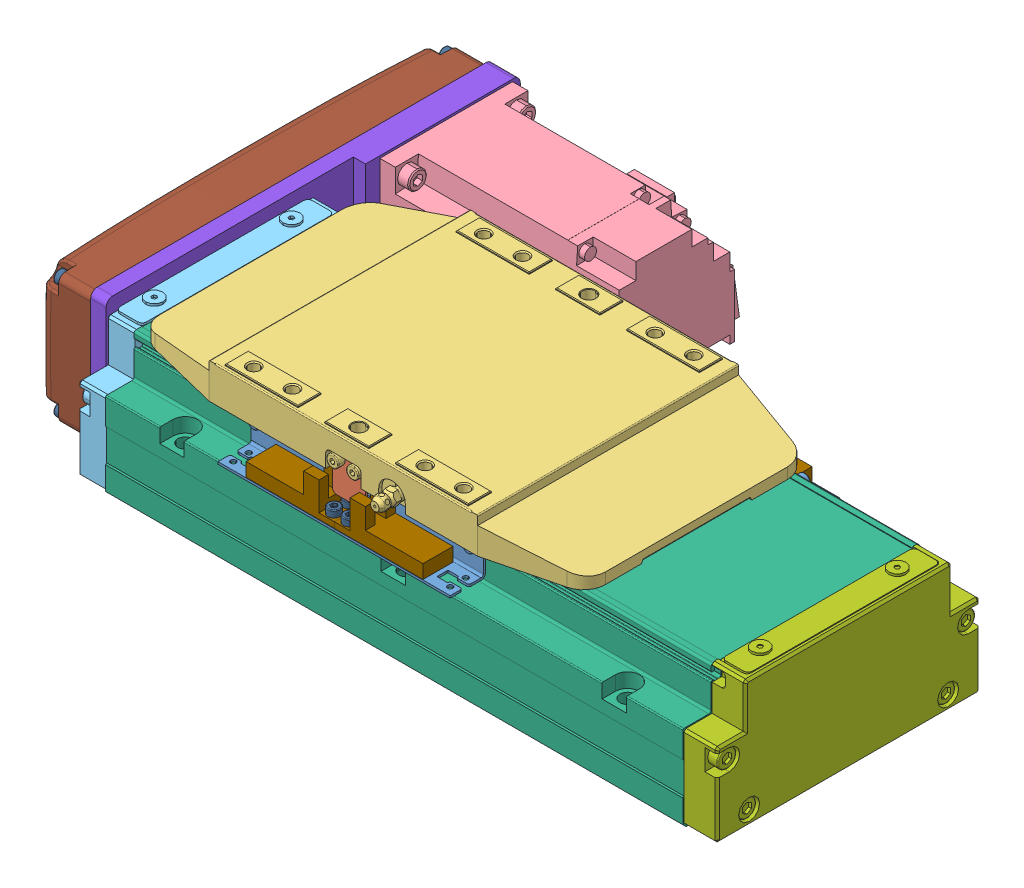
SolidWorks assembly G12-BR-400W, configuration Default. Lengths in mm.
Overall size (320.5 76 207.1).
25 component instances, 11 part files, 62 mates.
Components (placement in the parent):
- 304开关座片G5-12^G12-BR-400W-1: 304开关座片G5-12^G12-BR-400W [Default] at (209 38.5 -47.2) x (-1 0 0) z (0 0 -1) size (52.5 15.7 21) (virtual)
- 304开关座片G5-12^G12-BR-400W-2: 304开关座片G5-12^G12-BR-400W [Default] at (54 38.5 47.2) size (52.5 15.7 21) (virtual)
- 304开关座片G5-12^G12-BR-400W-3: 304开关座片G5-12^G12-BR-400W [Default] at (106.5 38.5 47.2) size (52.5 15.7 21) (virtual)
- 304感应片G8-12^G12-BR-400W-1: 304感应片G8-12^G12-BR-400W [Default] at (106.5 56.7 0) x (1 0 0) z (0 0 -1) size (15 17 1) (virtual)
- 304感应片G8-12^G12-BR-400W-2: 304感应片G8-12^G12-BR-400W [Default] at (106.5 56.7 0) x (-1 0 0) z (0 0 1) size (15 17 1) (virtual)
- 滑台G12^G12-BR-400W-1: 滑台G12^G12-BR-400W [Default] at (106.5 59.3 0) size (201.5 16.7 133.6) (virtual)
- 三菱400w^G12-BR-400W-1: 三菱400w^G12-BR-400W [Default] at (-7.5 32.5 -101.5) x (0 0 -1) z (0 -1 0) size (68.8 128.3 60) (virtual)
- 丝杆座板G12^G12-BR-400W-1: 丝杆座板G12^G12-BR-400W [Default] at origin size (20.5 58.7 119) (virtual)
- 复件 复件 底座GY12+211^G12-BR-400W-1: 复件 复件 底座GY12+211^G12-BR-400W [默认] x (0 0 -1) z (1 0 0) size (120 58 261) (virtual)
- 塑胶轴承座G12^G12-BR-400W-2: 塑胶轴承座G12^G12-BR-400W [Default] at (261 0 0) size (15 58.9 119) (virtual)
- 电机板G12-BLR-P60^G12-BR-400W-1: 电机板G12-BLR-P60^G12-BR-400W [Default] at (0 65 0) x (1 0 0) z (0 0 -1) size (12.5 62 181.75) (virtual)
- 复件 复件 光电开关EE-SX674^G12-BR-400W-1: 复件 复件 光电开关EE-SX674^G12-BR-400W [默认] at (66.5 41.8 49.4) size (40 15.5 13.6) (virtual)
- 复件 复件 光电开关EE-SX674^G12-BR-400W-2: 复件 复件 光电开关EE-SX674^G12-BR-400W [默认] at (146.5 41.8 63) x (-1 0 0) z (0 0 -1) size (40 15.5 13.6) (virtual)
- 复件 复件 光电开关EE-SX674^G12-BR-400W-3: 复件 复件 光电开关EE-SX674^G12-BR-400W [默认] at (196.5 41.8 -49.4) x (-1 0 0) z (0 0 -1) size (40 15.5 13.6) (virtual)
- hexagon socket head cap screws gb-5: hexagon socket head cap screws gb [GB_FASTENER_SCREWS_HSHCS M3X5-N] at (160 47.4 -52.7) x (0 -1 0) z (0 0 1) size (8 5.5 5.5)
- hexagon socket head cap screws gb-6: hexagon socket head cap screws gb [GB_FASTENER_SCREWS_HSHCS M3X5-N] at (160 47.4 -59.7) x (0 -1 0) z (0 0 1) size (8 5.5 5.5)
- hexagon socket head cap screws gb-7: hexagon socket head cap screws gb [GB_FASTENER_SCREWS_HSHCS M3X5-N] at (103 47.4 59.7) x (0 -1 0) z (0 0 1) size (8 5.5 5.5)
- hexagon socket head cap screws gb-8: hexagon socket head cap screws gb [GB_FASTENER_SCREWS_HSHCS M3X5-N] at (103 47.4 52.7) x (0 -1 0) z (0 0 1) size (8 5.5 5.5)
- hexagon socket head cap screws gb-9: hexagon socket head cap screws gb [GB_FASTENER_SCREWS_HSHCS M3X5-N] at (110 47.4 59.7) x (0 -1 0) z (0 0 1) size (8 5.5 5.5)
- hexagon socket head cap screws gb-10: hexagon socket head cap screws gb [GB_FASTENER_SCREWS_HSHCS M3X5-N] at (110 47.4 52.7) x (0 -1 0) z (0 0 1) size (8 5.5 5.5)
- hexagon socket head cap screws gb-11: hexagon socket head cap screws gb [GB_FASTENER_SCREWS_HSHCS M3X20-N] at (-38 58.5 -131.125) size (23 5.5 5.5)
- hexagon socket head cap screws gb-12: hexagon socket head cap screws gb [GB_FASTENER_SCREWS_HSHCS M3X20-N] at (-38 6.5 -131.125) size (23 5.5 5.5)
- hexagon socket head cap screws gb-13: hexagon socket head cap screws gb [GB_FASTENER_SCREWS_HSHCS M3X20-N] at (-38 6.5 42.875) size (23 5.5 5.5)
- hexagon socket head cap screws gb-14: hexagon socket head cap screws gb [GB_FASTENER_SCREWS_HSHCS M3X20-N] at (-38 58.5 42.875) size (23 5.5 5.5)
- 复件 同步轮罩壳G12^G12-BR-400W-2: 复件 同步轮罩壳G12^G12-BR-400W [默认] at (-43.3 32.5 -44.125) x (0 0 1) z (0 1 0) size (180.75 24.5 61.51) (virtual)
Mates (geometry in assembly coordinates):
- 宽度3: width: plane of 丝杆座板G12^G12-BR-400W-1 through (-13 37.5 59.5) normal (0 0 1); plane of 丝杆座板G12^G12-BR-400W-1 through (-13 2 -59.5) normal (0 0 -1); plane of 复件 复件 底座GY12+211^G12-BR-400W-1 through (261 12.5 -59.5) normal (0 0 -1); plane of 复件 复件 底座GY12+211^G12-BR-400W-1 through (261 26.5 59.5) normal (0 0 1)
- 距离2: distance = 1 mm: plane of 复件 复件 底座GY12+211^G12-BR-400W-1 through (261 0 58.5) normal (0 -1 0); plane of 丝杆座板G12^G12-BR-400W-1 through (-13 1 58.5) normal (0 -1 0)
- 重合11: coincident: plane of 丝杆座板G12^G12-BR-400W-1 through (0 0 0) normal (1 0 0); plane of 复件 复件 底座GY12+211^G12-BR-400W-1 through (0 57 46.2) normal (-1 0 0)
- 宽度8: width: plane of 滑台G12^G12-BR-400W-1 through (45.75 76 59) normal (0 0 1); plane of 滑台G12^G12-BR-400W-1 through (167.25 76 -59) normal (0 0 -1); plane of 复件 复件 底座GY12+211^G12-BR-400W-1 through (261 12.5 -59.5) normal (0 0 -1); plane of 复件 复件 底座GY12+211^G12-BR-400W-1 through (261 26.5 59.5) normal (0 0 1)
- 距离5: distance = 76 mm: plane of 滑台G12^G12-BR-400W-1 through (15.75 76 -41.214) normal (0 1 0); plane of 复件 复件 底座GY12+211^G12-BR-400W-1 through (261 0 58.5) normal (0 -1 0)
- 宽度9: width: plane of 304感应片G8-12^G12-BR-400W-2 through (99 64 56.5) normal (-1 0 0); plane of 304感应片G8-12^G12-BR-400W-2 through (114 51 56.5) normal (1 0 0); plane of 滑台G12^G12-BR-400W-1 through (98.5 65 55.5) normal (1 0 0); plane of 滑台G12^G12-BR-400W-1 through (114.5 59.3 55.5) normal (-1 0 0)
- 距离6: distance = 10.3 mm: plane of 304感应片G8-12^G12-BR-400W-2 through (101 49 56.5) normal (0 -1 0); plane of 滑台G12^G12-BR-400W-1 through (15.75 59.3 -41.214) normal (0 -1 0)
- 距离7: distance = 2.5 mm: plane of 304感应片G8-12^G12-BR-400W-2 through (112 51 56.5) normal (0 0 1); plane of 滑台G12^G12-BR-400W-1 through (45.75 76 59) normal (0 0 1)
- 宽度10: width: plane of 304感应片G8-12^G12-BR-400W-1 through (99 51 -56.5) normal (-1 0 0); plane of 304感应片G8-12^G12-BR-400W-1 through (114 64 -56.5) normal (1 0 0); plane of 滑台G12^G12-BR-400W-1 through (98.5 65 -55.5) normal (1 0 0); plane of 滑台G12^G12-BR-400W-1 through (114.5 59.3 -55.5) normal (-1 0 0)
- 距离8: distance = 2.5 mm: plane of 304感应片G8-12^G12-BR-400W-1 through (101 51 -56.5) normal (0 0 -1); plane of 滑台G12^G12-BR-400W-1 through (167.25 76 -59) normal (0 0 -1)
- 距离9: distance = 10.3 mm: plane of 304感应片G8-12^G12-BR-400W-1 through (112 49 -56.5) normal (0 -1 0); plane of 滑台G12^G12-BR-400W-1 through (15.75 59.3 -41.214) normal (0 -1 0)
- 宽度14: width: plane of 塑胶轴承座G12^G12-BR-400W-2 through (276 37.5 59.5) normal (0 0 1); plane of 塑胶轴承座G12^G12-BR-400W-2 through (276 2 -59.5) normal (0 0 -1); plane of 复件 复件 底座GY12+211^G12-BR-400W-1 through (261 12.5 -59.5) normal (0 0 -1); plane of 复件 复件 底座GY12+211^G12-BR-400W-1 through (261 26.5 59.5) normal (0 0 1)
- 重合23: coincident: plane of 复件 复件 底座GY12+211^G12-BR-400W-1 through (261 57 46.2) normal (1 0 0); plane of 塑胶轴承座G12^G12-BR-400W-2 through (261 0 0) normal (-1 0 0)
- 距离10: distance = 1 mm: plane of 塑胶轴承座G12^G12-BR-400W-2 through (276 1 58.5) normal (0 -1 0); plane of 复件 复件 底座GY12+211^G12-BR-400W-1 through (261 0 58.5) normal (0 -1 0)
- 距离11: distance = 67 mm: plane of 304开关座片G5-12^G12-BR-400W-2 through (54 42.8 49.2) normal (-1 0 0); plane of 丝杆座板G12^G12-BR-400W-1 through (-13 0 0) normal (-1 0 0)
- 距离12: distance = 105 mm: plane of 304开关座片G5-12^G12-BR-400W-3 through (159 42.8 49.2) normal (1 0 0); plane of 304开关座片G5-12^G12-BR-400W-2 through (54 42.8 49.2) normal (-1 0 0)
- 宽度15: width: plane of 复件 复件 底座GY12+211^G12-BR-400W-1 through (261 51.25 46.2) normal (0 1 0); plane of 复件 复件 底座GY12+211^G12-BR-400W-1 through (261 54.75 46.7) normal (0 -1 0); cylinder of 304开关座片G5-12^G12-BR-400W-2 through (58 53 42.2) axis (0 0 -1) radius 2.75
- 重合28: coincident: plane of 304开关座片G5-12^G12-BR-400W-2 through (106.5 40.8 63.2) normal (0 -1 0); plane of 304开关座片G5-12^G12-BR-400W-3 through (159 40.8 63.2) normal (0 -1 0)
- 重合29: coincident: plane of 304开关座片G5-12^G12-BR-400W-2 through (106.5 56.5 48.2) normal (0 0 1); plane of 304开关座片G5-12^G12-BR-400W-3 through (159 56.5 48.2) normal (0 0 1)
- 重合30: coincident: plane of 304开关座片G5-12^G12-BR-400W-2 through (106.5 42.8 47.2) normal (0 0 -1); plane of 复件 复件 底座GY12+211^G12-BR-400W-1 through (261 50.75 47.2) normal (0 0 1)
- 宽度16: width: plane of 复件 复件 底座GY12+211^G12-BR-400W-1 through (261 51.25 -46.7) normal (0 1 0); plane of 复件 复件 底座GY12+211^G12-BR-400W-1 through (261 54.75 -46.2) normal (0 -1 0); cylinder of 304开关座片G5-12^G12-BR-400W-1 through (205 53 -42.2) axis (0 0 1) radius 2.75
- 重合36: coincident: plane of 304开关座片G5-12^G12-BR-400W-1 through (156.5 42.8 -47.2) normal (0 0 1); plane of 复件 复件 底座GY12+211^G12-BR-400W-1 through (261 40 -47.2) normal (0 0 -1)
- 重合39: coincident: plane of 丝杆座板G12^G12-BR-400W-1 through (-13 0 0) normal (-1 0 0); plane of 电机板G12-BLR-P60^G12-BR-400W-1 through (-13 60.5 -132) normal (1 0 0)
- 重合43: coincident: plane of 三菱400w^G12-BR-400W-1 through (-7.5 32.5 -101.5) normal (-1 0 0); plane of 电机板G12-BLR-P60^G12-BR-400W-1 through (-7.5 60.5 -132) normal (1 0 0)
- 距离15: distance = 12.75 mm: plane of 复件 复件 底座GY12+211^G12-BR-400W-1 through (261 26.5 59.5) normal (0 0 1); plane of 电机板G12-BLR-P60^G12-BR-400W-1 through (-59.5 60.5 46.75) normal (0 0 1)
- 距离16: distance = 1.5 mm: plane of 电机板G12-BLR-P60^G12-BR-400W-1 through (-59.5 1.5 43.75) normal (0 -1 0); plane of 复件 复件 底座GY12+211^G12-BR-400W-1 through (261 0 58.5) normal (0 -1 0)
- 距离17: distance = 11.5 mm: plane of 复件 复件 底座GY12+211^G12-BR-400W-1 through (261 27 -60) normal (0 0 -1); plane of 三菱400w^G12-BR-400W-1 through (67 62.5 -71.5) normal (0 0 1)
- 宽度19: width: plane of 电机板G12-BLR-P60^G12-BR-400W-1 through (-59.5 1.5 43.75) normal (0 -1 0); plane of 电机板G12-BLR-P60^G12-BR-400W-1 through (-59.5 63.5 -132) normal (0 1 0); plane of 三菱400w^G12-BR-400W-1 through (67 62.5 -131.5) normal (0 1 0); plane of 三菱400w^G12-BR-400W-1 through (67 2.5 -71.5) normal (0 -1 0)
- 距离18: distance = 67 mm: plane of 304开关座片G5-12^G12-BR-400W-1 through (209 42.8 -49.2) normal (1 0 0); plane of 塑胶轴承座G12^G12-BR-400W-2 through (276 0 0) normal (1 0 0)
- 宽度20: width: plane of 304开关座片G5-12^G12-BR-400W-2 through (54 42.8 49.2) normal (-1 0 0); plane of 304开关座片G5-12^G12-BR-400W-3 through (159 42.8 49.2) normal (1 0 0); plane of 304感应片G8-12^G12-BR-400W-2 through (114 51 56.5) normal (1 0 0); plane of 304感应片G8-12^G12-BR-400W-2 through (99 64 56.5) normal (-1 0 0)
- 同心7: concentric: cylinder of 304开关座片G5-12^G12-BR-400W-2 through (103 43.5 59.7) axis (0 -1 0) radius 1.23; cylinder of 复件 复件 光电开关EE-SX674^G12-BR-400W-1 through (103 30.8 59.7) axis (0 1 0) radius 1.75
- 同心8: concentric: cylinder of 304开关座片G5-12^G12-BR-400W-2 through (103 43.5 52.7) axis (0 -1 0) radius 1.23; cylinder of 复件 复件 光电开关EE-SX674^G12-BR-400W-1 through (103 30.8 52.7) axis (0 1 0) radius 1.75
- 重合44: coincident: plane of 304开关座片G5-12^G12-BR-400W-2 through (106.5 41.8 49.2) normal (0 1 0); plane of 复件 复件 光电开关EE-SX674^G12-BR-400W-1 through (106.5 41.8 63) normal (0 -1 0)
- 重合45: coincident: plane of 304开关座片G5-12^G12-BR-400W-3 through (159 41.8 49.2) normal (0 1 0); plane of 复件 复件 光电开关EE-SX674^G12-BR-400W-2 through (106.5 41.8 49.4) normal (0 -1 0)
- 同心9: concentric: cylinder of 304开关座片G5-12^G12-BR-400W-3 through (110 43.5 59.7) axis (0 -1 0) radius 1.23; cylinder of 复件 复件 光电开关EE-SX674^G12-BR-400W-2 through (110 30.8 59.7) axis (0 1 0) radius 1.75
- 同心10: concentric: cylinder of 304开关座片G5-12^G12-BR-400W-3 through (110 43.5 52.7) axis (0 -1 0) radius 1.23; cylinder of 复件 复件 光电开关EE-SX674^G12-BR-400W-2 through (110 30.8 52.7) axis (0 1 0) radius 1.75
- 重合46: coincident: plane of 304开关座片G5-12^G12-BR-400W-1 through (156.5 41.8 -49.2) normal (0 1 0); plane of 复件 复件 光电开关EE-SX674^G12-BR-400W-3 through (156.5 41.8 -63) normal (0 -1 0)
- 同心11: concentric: cylinder of 304开关座片G5-12^G12-BR-400W-1 through (160 43.5 -52.7) axis (0 -1 0) radius 1.23; cylinder of 复件 复件 光电开关EE-SX674^G12-BR-400W-3 through (160 30.8 -52.7) axis (0 1 0) radius 1.75
- 同心12: concentric: cylinder of 304开关座片G5-12^G12-BR-400W-1 through (160 43.5 -59.7) axis (0 -1 0) radius 1.23; cylinder of 复件 复件 光电开关EE-SX674^G12-BR-400W-3 through (160 30.8 -59.7) axis (0 1 0) radius 1.75
- 重合51: coincident: plane of 复件 复件 光电开关EE-SX674^G12-BR-400W-3 through (163.5 44.4 -63) normal (0 1 0); plane of hexagon socket head cap screws gb-5 through (160 44.4 -52.7) normal (0 -1 0)
- 同心18: concentric: cylinder of 复件 复件 光电开关EE-SX674^G12-BR-400W-3 through (160 30.8 -52.7) axis (0 1 0) radius 1.75; cylinder of hexagon socket head cap screws gb-5 through (160 39.4 -52.7) axis (0 1 0) radius 1.5
- 重合52: coincident: plane of 复件 复件 光电开关EE-SX674^G12-BR-400W-3 through (163.5 44.4 -63) normal (0 1 0); plane of hexagon socket head cap screws gb-6 through (160 44.4 -59.7) normal (0 -1 0)
- 同心19: concentric: cylinder of 复件 复件 光电开关EE-SX674^G12-BR-400W-3 through (160 30.8 -59.7) axis (0 1 0) radius 1.75; cylinder of hexagon socket head cap screws gb-6 through (160 39.4 -59.7) axis (0 1 0) radius 1.5
- 重合53: coincident: plane of 复件 复件 光电开关EE-SX674^G12-BR-400W-1 through (99.5 44.4 63) normal (0 1 0); plane of hexagon socket head cap screws gb-7 through (103 44.4 59.7) normal (0 -1 0)
- 同心20: concentric: cylinder of 复件 复件 光电开关EE-SX674^G12-BR-400W-1 through (103 30.8 59.7) axis (0 1 0) radius 1.75; cylinder of hexagon socket head cap screws gb-7 through (103 39.4 59.7) axis (0 1 0) radius 1.5
- 重合54: coincident: plane of 复件 复件 光电开关EE-SX674^G12-BR-400W-1 through (99.5 44.4 63) normal (0 1 0); plane of hexagon socket head cap screws gb-8 through (103 44.4 52.7) normal (0 -1 0)
- 同心21: concentric: cylinder of 复件 复件 光电开关EE-SX674^G12-BR-400W-1 through (103 30.8 52.7) axis (0 1 0) radius 1.75; cylinder of hexagon socket head cap screws gb-8 through (103 39.4 52.7) axis (0 1 0) radius 1.5
- 重合55: coincident: plane of 复件 复件 光电开关EE-SX674^G12-BR-400W-2 through (113.5 44.4 49.4) normal (0 1 0); plane of hexagon socket head cap screws gb-9 through (110 44.4 59.7) normal (0 -1 0)
- 同心22: concentric: cylinder of 复件 复件 光电开关EE-SX674^G12-BR-400W-2 through (110 30.8 59.7) axis (0 1 0) radius 1.75; cylinder of hexagon socket head cap screws gb-9 through (110 39.4 59.7) axis (0 1 0) radius 1.5
- 重合56: coincident: plane of 复件 复件 光电开关EE-SX674^G12-BR-400W-2 through (113.5 44.4 49.4) normal (0 1 0); plane of hexagon socket head cap screws gb-10 through (110 44.4 52.7) normal (0 -1 0)
- 同心23: concentric: cylinder of 复件 复件 光电开关EE-SX674^G12-BR-400W-2 through (110 30.8 52.7) axis (0 1 0) radius 1.75; cylinder of hexagon socket head cap screws gb-10 through (110 39.4 52.7) axis (0 1 0) radius 1.5
- 重合57: coincident: plane of 电机板G12-BLR-P60^G12-BR-400W-1 through (-20 165 -200) normal (-1 0 0); plane of 复件 同步轮罩壳G12^G12-BR-400W-2 through (-20 32.5 -44.125) normal (1 0 0)
- 宽度21: width: plane of 电机板G12-BLR-P60^G12-BR-400W-1 through (-59.5 4.5 -135) normal (0 0 -1); plane of 电机板G12-BLR-P60^G12-BR-400W-1 through (-59.5 60.5 46.75) normal (0 0 1); plane of 复件 同步轮罩壳G12^G12-BR-400W-2 through (-20 63.25 -134.5) normal (0 0 -1); plane of 复件 同步轮罩壳G12^G12-BR-400W-2 through (-20 63.25 46.25) normal (0 0 1)
- 对称1: symmetric: plane of 电机板G12-BLR-P60^G12-BR-400W-1 through (-59.5 63.5 -132) normal (0 1 0); plane of 电机板G12-BLR-P60^G12-BR-400W-1 through (-59.5 1.5 43.75) normal (0 -1 0); plane of 复件 同步轮罩壳G12^G12-BR-400W-2 through (-43.3 32.5 -44.125) normal (0 1 0)
- 同心24: concentric: cylinder of hexagon socket head cap screws gb-11 through (-35 58.5 -131.125) axis (-1 0 0) radius 2.75; circle of 复件 同步轮罩壳G12^G12-BR-400W-2
- 重合58: coincident: plane of hexagon socket head cap screws gb-11 through (-35 58.5 -131.125) normal (1 0 0); plane of 复件 同步轮罩壳G12^G12-BR-400W-2 through (-35 58.5 -129.425) normal (-1 0 0)
- 同心25: concentric: cylinder of hexagon socket head cap screws gb-12 through (-35 6.5 -131.125) axis (-1 0 0) radius 2.75; cylinder of 复件 同步轮罩壳G12^G12-BR-400W-2 through (-44.5 6.5 -131.125) axis (-1 0 0) radius 1.7
- 重合59: coincident: plane of hexagon socket head cap screws gb-12 through (-35 6.5 -131.125) normal (1 0 0); plane of 复件 同步轮罩壳G12^G12-BR-400W-2 through (-35 6.5 -129.425) normal (-1 0 0)
- 重合60: coincident: plane of hexagon socket head cap screws gb-14 through (-35 58.5 42.875) normal (1 0 0); plane of 复件 同步轮罩壳G12^G12-BR-400W-2 through (-35 58.5 44.575) normal (-1 0 0)
- 同心26: concentric: cylinder of hexagon socket head cap screws gb-14 through (-35 58.5 42.875) axis (-1 0 0) radius 2.75; cylinder of 复件 同步轮罩壳G12^G12-BR-400W-2 through (-44.5 58.5 42.875) axis (-1 0 0) radius 1.7
- 同心27: concentric: cylinder of hexagon socket head cap screws gb-13 through (-35 6.5 42.875) axis (-1 0 0) radius 2.75; cylinder of 复件 同步轮罩壳G12^G12-BR-400W-2 through (-44.5 6.5 42.875) axis (-1 0 0) radius 1.7
- 重合61: coincident: plane of hexagon socket head cap screws gb-13 through (-35 6.5 42.875) normal (1 0 0); plane of 复件 同步轮罩壳G12^G12-BR-400W-2 through (-35 6.5 44.575) normal (-1 0 0)
